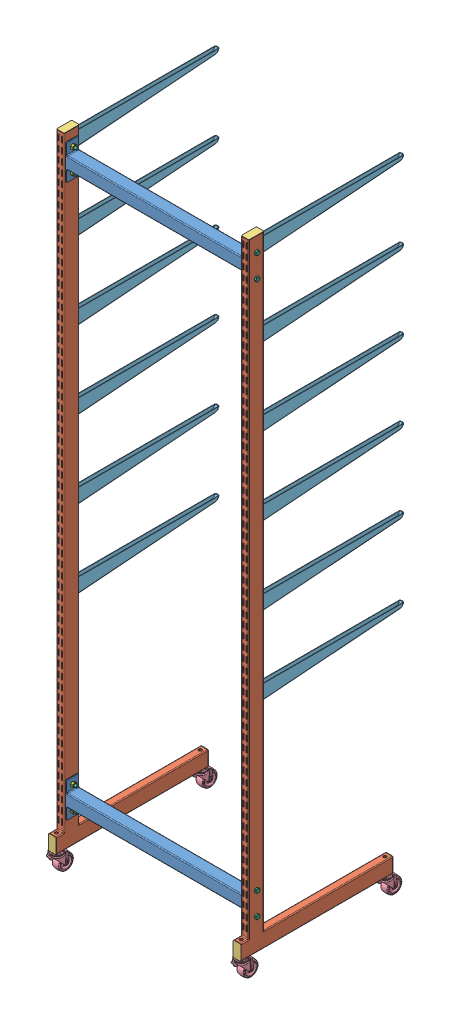
SolidWorks assembly Twin slot shelf, configuration Default. Lengths in mm.
Overall size (666.07 2115 554.23).
43 component instances, 8 part files, 104 mates.
Components (placement in the parent):
- TB-600-1: TB-600 [Default] at (0 2029.5 0) size (585 115 40)
- TB-600-2: TB-600 [Default] at (0 205.5 0) size (585 115 40)
- TSU-F-L-P-1: TSU-F-L-P [Default] at (305 113.5 -25) size (25 2050 500)
- TSU-F-L-P-2: TSU-F-L-P [Default] at (-305 113.5 -25) size (25 2050 500)
- TSU-CAP-1: TSU-CAP [Default] at (-305.1 113.6 -39.9) x (-1 0 0) z (0 0 -1) size (25.2 50.2 6.5)
- TSU-CAP-2: TSU-CAP [Default] at (304.9 113.6 -39.9) x (-1 0 0) z (0 0 -1) size (25.2 50.2 6.5)
- TSU-CAP-3: TSU-CAP [Default] at (305.1 1703.4 -25.1) x (1 0 0) z (0 1 0) size (25.2 50.2 6.5)
- TSU-CAP-4: TSU-CAP [Default] at (304.9 113.6 -360.1) size (25.2 50.2 6.5)
- TSU-CAP-5: TSU-CAP [Default] at (-304.9 1703.4 -25.1) x (1 0 0) z (0 1 0) size (25.2 50.2 6.5)
- TSU-CAP-6: TSU-CAP [Default] at (-304.9 113.6 -360.1) size (25.2 50.2 6.5)
- 2834T320_THREADED-STEM SWIVEL CASTER-1: 2834T320_THREADED-STEM SWIVEL CASTER [2834T32] at (305 82.55 -437.5) x (0 0 -1) z (1 0 0) size (67.73 101.87 56.07)
- 2834T320_THREADED-STEM SWIVEL CASTER-2: 2834T320_THREADED-STEM SWIVEL CASTER [2834T32] at (-305 82.55 37.5) x (0 0 -1) z (1 0 0) size (67.73 101.87 56.07)
- 2834T320_THREADED-STEM SWIVEL CASTER-3: 2834T320_THREADED-STEM SWIVEL CASTER [2834T32] at (305 82.55 37.5) x (0 0 -1) z (1 0 0) size (67.73 101.87 56.07)
- 2834T320_THREADED-STEM SWIVEL CASTER-4: 2834T320_THREADED-STEM SWIVEL CASTER [2834T32] at (-305 82.55 -437.5) x (0 0 -1) z (1 0 0) size (67.73 101.87 56.07)
- TSUB-1: TSUB [Default] at (305 766.5 -25) x (-1 0 0) z (0 0 -1) size (14.07 50.86 484.03)
- TSUB-2: TSUB [Default] at (-305 766.5 -25) x (-1 0 0) z (0 0 -1) size (14.07 50.86 484.03)
- TSUB-3: TSUB [Default] at (-305 1022.5 -25) x (-1 0 0) z (0 0 -1) size (14.07 50.86 484.03)
- TSUB-4: TSUB [Default] at (305 1022.5 -25) x (-1 0 0) z (0 0 -1) size (14.07 50.86 484.03)
- TSUB-5: TSUB [Default] at (-305 1534.5 -25) x (-1 0 0) z (0 0 -1) size (14.07 50.86 484.03)
- TSUB-6: TSUB [Default] at (305 1534.5 -25) x (-1 0 0) z (0 0 -1) size (14.07 50.86 484.03)
- TSUB-7: TSUB [Default] at (-305 2046.5 -25) x (-1 0 0) z (0 0 -1) size (14.07 50.86 484.03)
- TSUB-8: TSUB [Default] at (305 2046.5 -25) x (-1 0 0) z (0 0 -1) size (14.07 50.86 484.03)
- TSUB-9: TSUB [Default] at (-305 1278.5 -25) x (-1 0 0) z (0 0 -1) size (14.07 50.86 484.03)
- TSUB-10: TSUB [Default] at (305 1278.5 -25) x (-1 0 0) z (0 0 -1) size (14.07 50.86 484.03)
- TSUB-11: TSUB [Default] at (-305 1790.5 -25) x (-1 0 0) z (0 0 -1) size (14.07 50.86 484.03)
- TSUB-12: TSUB [Default] at (305 1790.5 -25) x (-1 0 0) z (0 0 -1) size (14.07 50.86 484.03)
- hex bolt gradeab2_bsi-10: hex bolt gradeab2_bsi [BS EN 28765 - M8x1 x 45 x 22-N] at (322.8 2067 0) x (-1 0 0) z (0 -0.924225 -0.381849) size (50.3 15.01 13)
- hex bolt gradeab2_bsi-11: hex bolt gradeab2_bsi [BS EN 28765 - M8x1 x 45 x 22-N] at (322.8 1992 0) x (-1 0 0) z (0 -0.999974 0.007224) size (50.3 15.01 13)
- hex bolt gradeab2_bsi-12: hex bolt gradeab2_bsi [BS EN 28765 - M8x1 x 45 x 22-N] at (-322.8 2067 0) size (50.3 15.01 13)
- hex bolt gradeab2_bsi-13: hex bolt gradeab2_bsi [BS EN 28765 - M8x1 x 45 x 22-N] at (-322.8 1992 0) size (50.3 15.01 13)
- hex bolt gradeab2_bsi-14: hex bolt gradeab2_bsi [BS EN 28765 - M8x1 x 45 x 22-N] at (-322.8 168 0) size (50.3 15.01 13)
- hex bolt gradeab2_bsi-15: hex bolt gradeab2_bsi [BS EN 28765 - M8x1 x 45 x 22-N] at (-322.8 243 0) size (50.3 15.01 13)
- hex bolt gradeab2_bsi-16: hex bolt gradeab2_bsi [BS EN 28765 - M8x1 x 45 x 22-N] at (322.8 168 0) x (-1 0 0) z (0 0.924225 0.381849) size (50.3 15.01 13)
- hex bolt gradeab2_bsi-17: hex bolt gradeab2_bsi [BS EN 28765 - M8x1 x 45 x 22-N] at (322.8 243 0) x (-1 0 0) z (0 -0.924225 -0.381849) size (50.3 15.01 13)
- hex nut gradec_bsi-1: hex nut gradec_bsi [BS EN 24034 - M8 - N] at (281.6 2067 0) x (0 0 1) z (-1 0 0) size (13 15.01 7.9)
- hex nut gradec_bsi-2: hex nut gradec_bsi [BS EN 24034 - M8 - N] at (281.6 1992 0) x (0 0 1) z (-1 0 0) size (13 15.01 7.9)
- hex nut gradec_bsi-3: hex nut gradec_bsi [BS EN 24034 - M8 - N] at (-281.6 2067 0) x (0 0 -1) z (1 0 0) size (13 15.01 7.9)
- hex nut gradec_bsi-4: hex nut gradec_bsi [BS EN 24034 - M8 - N] at (-281.6 1992 0) x (0 0.383049 0.923728) z (1 0 0) size (13 15.01 7.9)
- hex nut gradec_bsi-5: hex nut gradec_bsi [BS EN 24034 - M8 - N] at (-281.6 243 0) x (0 0 -1) z (1 0 0) size (13 15.01 7.9)
- hex nut gradec_bsi-6: hex nut gradec_bsi [BS EN 24034 - M8 - N] at (281.6 243 0) x (0 0 1) z (-1 0 0) size (13 15.01 7.9)
- hex nut gradec_bsi-7: hex nut gradec_bsi [BS EN 24034 - M8 - N] at (281.6 168 0) x (0 0 1) z (-1 0 0) size (13 15.01 7.9)
- hex nut gradec_bsi-8: hex nut gradec_bsi [BS EN 24034 - M8 - N] at (-281.6 168 0) x (0 0 -1) z (1 0 0) size (13 15.01 7.9)
- Part4-1: Part4 [Default] at origin
Mates (geometry in assembly coordinates):
- Coincident5: coincident aligned: plane of TB-600-2 through (0 205.5 0) normal (1 0 0)
- Coincident6: coincident aligned: plane of TB-600-2 through (0 205.5 0) normal (0 0 1)
- Tangent1: tangent anti-aligned: torus of 2834T320_THREADED-STEM SWIVEL CASTER-1
- Concentric5: concentric anti-aligned: cylinder of TSU-F-L-P-1 through (305 113.5 -437.5) axis (0 -1 0) radius 5.1; cylinder of 2834T320_THREADED-STEM SWIVEL CASTER-1 through (305 101.6 -437.5) axis (0 1 0) radius 4.7625
- Coincident7: coincident anti-aligned: plane of TB-600-2 through (292.5 205.5 0) normal (1 0 0); plane of TSU-F-L-P-1 through (292.5 2113.5 -22) normal (-1 0 0)
- Concentric6: concentric anti-aligned: cylinder of TB-600-2 through (292.5 243 0) axis (-1 0 0) radius 4.5; cylinder of TSU-F-L-P-1 through (290.9 243 0) axis (1 0 0) radius 4.5
- Coincident8: coincident anti-aligned: plane of TSU-F-L-P-1 through (305 63.5 -450) normal (0 -1 0); plane of 2834T320_THREADED-STEM SWIVEL CASTER-1 through (305 63.5 -421.3957) normal (0 1 0)
- Concentric7: concentric anti-aligned: cylinder of TB-600-1 through (292.5 2067 0) axis (-1 0 0) radius 4.5; cylinder of TSU-F-L-P-1 through (292.5 2067 0) axis (1 0 0) radius 4.5
- Coincident9: coincident anti-aligned: plane of TB-600-1 through (292.5 2029.5 0) normal (1 0 0); plane of TSU-F-L-P-1 through (292.5 2113.5 -22) normal (-1 0 0)
- Concentric8: concentric aligned: cylinder of TB-600-2 through (-292.5 168 0) axis (1 0 0) radius 4.5; cylinder of TSU-F-L-P-2 through (-319.1 168 0) axis (1 0 0) radius 4.5
- Coincident10: coincident anti-aligned: plane of TB-600-2 through (-292.5 205.5 0) normal (-1 0 0); plane of TSU-F-L-P-2 through (-292.5 2113.5 -22) normal (1 0 0)
- Concentric9: concentric anti-aligned: cylinder of TSU-F-L-P-2 through (-305 113.5 -437.5) axis (0 -1 0) radius 5.1; cylinder of 2834T320_THREADED-STEM SWIVEL CASTER-4 through (-305 101.6 -437.5) axis (0 1 0) radius 4.7625
- Concentric10: concentric aligned: cylinder of TB-600-1 through (-292.5 1992 0) axis (1 0 0) radius 4.5; cylinder of TSU-F-L-P-2 through (-317.5 1992 0) axis (1 0 0) radius 4.5
- Concentric11: concentric aligned: cylinder of TB-600-1 through (-292.5 2067 0) axis (1 0 0) radius 4.5; cylinder of TSU-F-L-P-2 through (-317.5 2067 0) axis (1 0 0) radius 4.5
- Parallel4: parallel aligned: plane of TSU-F-L-P-1 through (317.5 2113.5 -22) normal (1 0 0); plane of 2834T320_THREADED-STEM SWIVEL CASTER-1 through (316.9062 47.2916 -458.1375) normal (1 0 0)
- Coincident16: coincident anti-aligned: plane of TSU-F-L-P-2 through (-305 63.5 -450) normal (0 -1 0); plane of 2834T320_THREADED-STEM SWIVEL CASTER-4 through (-305 63.5 -421.3957) normal (0 1 0)
- Concentric12: concentric anti-aligned: cylinder of TSU-F-L-P-1 through (305 113.5 37.5) axis (0 -1 0) radius 5.1; cylinder of 2834T320_THREADED-STEM SWIVEL CASTER-3 through (305 101.6 37.5) axis (0 1 0) radius 4.7625
- Coincident17: coincident anti-aligned: plane of TSU-F-L-P-1 through (305 63.5 -450) normal (0 -1 0); plane of 2834T320_THREADED-STEM SWIVEL CASTER-3 through (305 63.5 53.6043) normal (0 1 0)
- Coincident18: coincident aligned: plane of 2834T320_THREADED-STEM SWIVEL CASTER-1 through (316.9062 47.2916 -458.1375) normal (1 0 0); plane of 2834T320_THREADED-STEM SWIVEL CASTER-3 through (316.9062 47.2916 16.8625) normal (1 0 0)
- Concentric13: concentric anti-aligned: cylinder of TSU-F-L-P-2 through (-305 113.5 37.5) axis (0 -1 0) radius 5.1; cylinder of 2834T320_THREADED-STEM SWIVEL CASTER-2 through (-305 101.6 37.5) axis (0 1 0) radius 4.7625
- Coincident19: coincident anti-aligned: plane of TSU-F-L-P-2 through (-305 63.5 -450) normal (0 -1 0); plane of 2834T320_THREADED-STEM SWIVEL CASTER-2 through (-305 63.5 53.6043) normal (0 1 0)
- Parallel6: parallel aligned: plane of TSU-F-L-P-2 through (-317.5 2113.5 -22) normal (-1 0 0); plane of 2834T320_THREADED-STEM SWIVEL CASTER-2 through (-316.9062 47.2916 16.8625) normal (-1 0 0)
- Coincident21: coincident anti-aligned: plane of TSU-F-L-P-1 through (294 2113.5 0) normal (1 0 0); plane of TSU-CAP-4 through (294 113.6 45) normal (-1 0 0)
- Coincident22: coincident anti-aligned: plane of TSU-F-L-P-1 through (314.5 112 -450) normal (0 -1 0); plane of TSU-CAP-4 through (304.9 112 45) normal (0 1 0)
- Coincident23: coincident anti-aligned: plane of TSU-F-L-P-1 through (314.5 110.5 50) normal (0 0 1); plane of TSU-CAP-4 through (304.9 113.6 50) normal (0 0 -1)
- Coincident24: coincident anti-aligned: plane of TSU-F-L-P-2 through (-294 2113.5 0) normal (-1 0 0); plane of TSU-CAP-6 through (-294 113.6 45) normal (1 0 0)
- Coincident25: coincident anti-aligned: plane of TSU-F-L-P-2 through (-295.5 112 -450) normal (0 -1 0); plane of TSU-CAP-6 through (-304.9 112 45) normal (0 1 0)
- Coincident26: coincident anti-aligned: plane of TSU-F-L-P-2 through (-295.5 110.5 50) normal (0 0 1); plane of TSU-CAP-6 through (-304.9 113.6 50) normal (0 0 -1)
- Coincident27: coincident anti-aligned: plane of TSU-F-L-P-1 through (294 2113.5 0) normal (1 0 0); plane of TSU-CAP-2 through (294 113.6 -445) normal (-1 0 0)
- Coincident28: coincident anti-aligned: plane of TSU-F-L-P-1 through (314.5 112 -450) normal (0 -1 0); plane of TSU-CAP-2 through (304.9 112 -445) normal (0 1 0)
- Coincident29: coincident anti-aligned: plane of TSU-F-L-P-1 through (314.5 110.5 -450) normal (0 0 -1); plane of TSU-CAP-2 through (304.9 113.6 -450) normal (0 0 1)
- Coincident30: coincident anti-aligned: plane of TSU-F-L-P-2 through (-316 2113.5 0) normal (1 0 0); plane of TSU-CAP-1 through (-316 113.6 -445) normal (-1 0 0)
- Coincident31: coincident anti-aligned: plane of TSU-F-L-P-2 through (-295.5 112 -450) normal (0 -1 0); plane of TSU-CAP-1 through (-305.1 112 -445) normal (0 1 0)
- Coincident32: coincident anti-aligned: plane of TSU-F-L-P-2 through (-295.5 110.5 -450) normal (0 0 -1); plane of TSU-CAP-1 through (-305.1 113.6 -450) normal (0 0 1)
- Coincident33: coincident anti-aligned: plane of TSU-F-L-P-1 through (316 2113.5 0) normal (-1 0 0); plane of TSU-CAP-3 through (316 2108.5 -25.1) normal (1 0 0)
- Coincident34: coincident anti-aligned: plane of TSU-F-L-P-1 through (314.5 2113.5 -23.5) normal (0 0 1); plane of TSU-CAP-3 through (305.1 2108.5 -23.5) normal (0 0 -1)
- Coincident35: coincident anti-aligned: plane of TSU-F-L-P-1 through (314.5 2113.5 -22) normal (0 1 0); plane of TSU-CAP-3 through (305.1 2113.5 -25.1) normal (0 -1 0)
- Coincident36: coincident anti-aligned: plane of TSU-F-L-P-2 through (-294 2113.5 0) normal (-1 0 0); plane of TSU-CAP-5 through (-294 2108.5 -25.1) normal (1 0 0)
- Coincident37: coincident anti-aligned: plane of TSU-F-L-P-2 through (-295.5 2113.5 -23.5) normal (0 0 1); plane of TSU-CAP-5 through (-304.9 2108.5 -23.5) normal (0 0 -1)
- Coincident38: coincident anti-aligned: plane of TSU-F-L-P-2 through (-295.5 2113.5 -22) normal (0 1 0); plane of TSU-CAP-5 through (-304.9 2113.5 -25.1) normal (0 -1 0)
- Parallel7: parallel aligned: plane of TSU-F-L-P-2 through (-292.5 2113.5 -22) normal (1 0 0); plane of 2834T320_THREADED-STEM SWIVEL CASTER-4 through (-293.0938 47.2916 -458.1375) normal (1 0 0)
- Coincident41: coincident anti-aligned: plane of TSU-F-L-P-1 through (298 273.5 0.001) normal (1 0 0); plane of TSUB-1 through (298 766.5 -25) normal (-1 0 0)
- Coincident42: coincident anti-aligned: plane of TSU-F-L-P-1 through (305 2113.5 -25) normal (0 0 -1); plane of TSUB-1 through (312 766.5 -25) normal (0 0 1)
- Parallel8: parallel: line of TSU-F-L-P-1 through (309 342 -23.5) axis (0 0 -1); plane of TSUB-1 through (298 816.5 -25) normal (0 1 0)
- Coincident46: coincident anti-aligned: plane of TSU-F-L-P-2 through (-312 369.5 0.001) normal (1 0 0); plane of TSUB-2 through (-312 766.5 -25) normal (-1 0 0)
- Coincident47: coincident anti-aligned: plane of TSU-F-L-P-2 through (-305 2113.5 -25) normal (0 0 -1); plane of TSUB-2 through (-312 766.5 -25) normal (0 0 1)
- Coincident49: coincident anti-aligned: plane of TSU-F-L-P-1 through (312 1041.5 0.001) normal (-1 0 0); plane of TSUB-4 through (312 1022.5 -25) normal (1 0 0)
- Coincident50: coincident anti-aligned: plane of TSU-F-L-P-1 through (305 2113.5 -25) normal (0 0 -1); plane of TSUB-4 through (312 1022.5 -25) normal (0 0 1)
- Coincident51: coincident anti-aligned: plane of TSU-F-L-P-2 through (-298 1073.5 0.001) normal (-1 0 0); plane of TSUB-3 through (-298 1022.5 -25) normal (1 0 0)
- Coincident52: coincident anti-aligned: plane of TSU-F-L-P-2 through (-305 2113.5 -25) normal (0 0 -1); plane of TSUB-3 through (-312 1022.5 -25) normal (0 0 1)
- Coincident70: coincident anti-aligned: plane of TSU-F-L-P-1 through (305 2113.5 -25) normal (0 0 -1); plane of TSUB-10 through (298 1278.5 -25) normal (0 0 1)
- Coincident71: coincident anti-aligned: plane of TSU-F-L-P-2 through (-305 2113.5 -25) normal (0 0 -1); plane of TSUB-9 through (-312 1278.5 -25) normal (0 0 1)
- Coincident72: coincident aligned: plane of TSUB-3 through (-298 1022.5 -25) normal (1 0 0); plane of TSUB-9 through (-298 1278.5 -25) normal (1 0 0)
- Coincident73: coincident aligned: plane of TSUB-4 through (298 1022.5 -25) normal (-1 0 0); plane of TSUB-10 through (298 1278.5 -25) normal (-1 0 0)
- Coincident74: coincident anti-aligned: plane of TSU-F-L-P-1 through (305 2113.5 -25) normal (0 0 -1); plane of TSUB-6 through (298 1534.5 -25) normal (0 0 1)
- Coincident75: coincident anti-aligned: plane of TSU-F-L-P-2 through (-305 2113.5 -25) normal (0 0 -1); plane of TSUB-5 through (-312 1534.5 -25) normal (0 0 1)
- Coincident76: coincident aligned: plane of TSUB-5 through (-298 1534.5 -25) normal (1 0 0); plane of TSUB-9 through (-298 1278.5 -25) normal (1 0 0)
- Coincident78: coincident aligned: plane of TSUB-6 through (312 1534.5 -25) normal (1 0 0); plane of TSUB-12 through (312 1790.5 -25) normal (1 0 0)
- Coincident79: coincident aligned: plane of TSUB-6 through (298 1534.5 -25) normal (-1 0 0); plane of TSUB-10 through (298 1278.5 -25) normal (-1 0 0)
- Coincident80: coincident anti-aligned: plane of TSU-F-L-P-1 through (305 2113.5 -25) normal (0 0 -1); plane of TSUB-12 through (298 1790.5 -25) normal (0 0 1)
- Coincident81: coincident anti-aligned: plane of TSU-F-L-P-2 through (-312 1873.5 0.001) normal (1 0 0); plane of TSUB-11 through (-312 1790.5 -25) normal (-1 0 0)
- Coincident82: coincident anti-aligned: plane of TSU-F-L-P-2 through (-305 2113.5 -25) normal (0 0 -1); plane of TSUB-11 through (-312 1790.5 -25) normal (0 0 1)
- Coincident83: coincident anti-aligned: plane of TSU-F-L-P-2 through (-312 1969.5 0.001) normal (1 0 0); plane of TSUB-7 through (-312 2046.5 -25) normal (-1 0 0)
- Coincident84: coincident anti-aligned: plane of TSU-F-L-P-2 through (-305 2113.5 -25) normal (0 0 -1); plane of TSUB-7 through (-312 2046.5 -25) normal (0 0 1)
- Coincident85: coincident anti-aligned: plane of TSU-F-L-P-1 through (298 2001.5 0.001) normal (1 0 0); plane of TSUB-8 through (298 2046.5 -25) normal (-1 0 0)
- Coincident86: coincident anti-aligned: plane of TSU-F-L-P-1 through (305 2113.5 -25) normal (0 0 -1); plane of TSUB-8 through (298 2046.5 -25) normal (0 0 1)
- Coincident89: coincident: line of TSU-F-L-P-1 through (309 2070 -23.5) axis (0 0 -1); plane of TSUB-8 through (333.2603 2070 -25) normal (0 1 0)
- Coincident153: coincident: line of TSU-F-L-P-1 through (312 1814 -23.5) axis (0 0 -1); plane of TSUB-12 through (333.2603 1814 -25) normal (0 1 0)
- Coincident155: coincident: line of TSU-F-L-P-1 through (312 1558 -23.5) axis (0 0 -1); plane of TSUB-6 through (333.2603 1558 -25) normal (0 1 0)
- Coincident157: coincident: line of TSU-F-L-P-1 through (312 1302 -23.5) axis (0 0 -1); plane of TSUB-10 through (333.2603 1302 -25) normal (0 1 0)
- Coincident159: coincident: line of TSU-F-L-P-1 through (312 1046 -23.5) axis (0 0 -1); plane of TSUB-4 through (333.2603 1046 -25) normal (0 1 0)
- Coincident167: coincident: line of TSU-F-L-P-1 through (312 790 -23.5) axis (0 0 -1); plane of TSUB-1 through (333.2603 790 -25) normal (0 1 0)
- Concentric15: concentric aligned: cylinder of TSU-F-L-P-1 through (292.5 2067 0) axis (1 0 0) radius 4.5; cylinder of hex bolt gradeab2_bsi-10 through (322.8 2067 0) axis (1 0 0) radius 4
- Coincident181: coincident anti-aligned: plane of TSU-F-L-P-1 through (317.5 2113.5 -22) normal (1 0 0); plane of hex bolt gradeab2_bsi-10 through (317.5 2069.866 -6.9368) normal (-1 0 0)
- Concentric16: concentric aligned: cylinder of TSU-F-L-P-1 through (292.5 1992 0) axis (1 0 0) radius 4.5; cylinder of hex bolt gradeab2_bsi-11 through (322.8 1992 0) axis (1 0 0) radius 4
- Coincident182: coincident anti-aligned: plane of TSU-F-L-P-1 through (317.5 2113.5 -22) normal (1 0 0); plane of hex bolt gradeab2_bsi-11 through (317.5 1991.9458 -7.5054) normal (-1 0 0)
- Concentric17: concentric anti-aligned: cylinder of TB-600-1 through (-292.5 2067 0) axis (1 0 0) radius 4.5; cylinder of hex bolt gradeab2_bsi-12 through (-322.8 2067 0) axis (-1 0 0) radius 4
- Coincident183: coincident anti-aligned: plane of TSU-F-L-P-2 through (-317.5 2113.5 -22) normal (-1 0 0); plane of hex bolt gradeab2_bsi-12 through (-317.5 2074.5056 0) normal (1 0 0)
- Concentric18: concentric anti-aligned: cylinder of TB-600-1 through (-292.5 1992 0) axis (1 0 0) radius 4.5; cylinder of hex bolt gradeab2_bsi-13 through (-322.8 1992 0) axis (-1 0 0) radius 4
- Coincident184: coincident anti-aligned: plane of TSU-F-L-P-2 through (-317.5 2113.5 -22) normal (-1 0 0); plane of hex bolt gradeab2_bsi-13 through (-317.5 1999.5056 0) normal (1 0 0)
- Concentric19: concentric anti-aligned: cylinder of TB-600-2 through (-292.5 243 0) axis (1 0 0) radius 4.5; cylinder of hex bolt gradeab2_bsi-15 through (-322.8 243 0) axis (-1 0 0) radius 4
- Coincident185: coincident anti-aligned: plane of TSU-F-L-P-2 through (-317.5 2113.5 -22) normal (-1 0 0); plane of hex bolt gradeab2_bsi-15 through (-317.5 250.5056 0) normal (1 0 0)
- Concentric20: concentric anti-aligned: cylinder of TB-600-2 through (-292.5 168 0) axis (1 0 0) radius 4.5; cylinder of hex bolt gradeab2_bsi-14 through (-322.8 168 0) axis (-1 0 0) radius 4
- Coincident186: coincident anti-aligned: plane of TSU-F-L-P-2 through (-317.5 2113.5 -22) normal (-1 0 0); plane of hex bolt gradeab2_bsi-14 through (-317.5 175.5056 0) normal (1 0 0)
- Concentric21: concentric anti-aligned: cylinder of TB-600-2 through (292.5 243 0) axis (-1 0 0) radius 4.5; cylinder of hex bolt gradeab2_bsi-17 through (322.8 243 0) axis (1 0 0) radius 4
- Coincident187: coincident anti-aligned: plane of TSU-F-L-P-1 through (317.5 2113.5 -22) normal (1 0 0); plane of hex bolt gradeab2_bsi-17 through (317.5 245.866 -6.9368) normal (-1 0 0)
- Concentric22: concentric aligned: cylinder of TSU-F-L-P-1 through (290.9 168 0) axis (1 0 0) radius 4.5; cylinder of hex bolt gradeab2_bsi-16 through (322.8 168 0) axis (1 0 0) radius 4
- Coincident188: coincident anti-aligned: plane of TSU-F-L-P-1 through (317.5 2113.5 -22) normal (1 0 0); plane of hex bolt gradeab2_bsi-16 through (317.5 165.134 6.9368) normal (-1 0 0)
- Concentric23: concentric anti-aligned: cylinder of hex bolt gradeab2_bsi-10 through (322.8 2067 0) axis (1 0 0) radius 4; cylinder of hex nut gradec_bsi-1 through (289.5 2067 0) axis (-1 0 0) radius 3.4
- Coincident189: coincident anti-aligned: plane of TB-600-1 through (289.5 2029.5 0) normal (-1 0 0); plane of hex nut gradec_bsi-1 through (289.5 2074.5056 0) normal (1 0 0)
- Concentric24: concentric anti-aligned: cylinder of hex bolt gradeab2_bsi-11 through (322.8 1992 0) axis (1 0 0) radius 4; cylinder of hex nut gradec_bsi-2 through (289.5 1992 0) axis (-1 0 0) radius 3.4
- Coincident190: coincident anti-aligned: plane of TB-600-1 through (289.5 2029.5 0) normal (-1 0 0); plane of hex nut gradec_bsi-2 through (289.5 1999.5056 0) normal (1 0 0)
- Concentric25: concentric anti-aligned: cylinder of hex bolt gradeab2_bsi-12 through (-322.8 2067 0) axis (-1 0 0) radius 4; cylinder of hex nut gradec_bsi-3 through (-289.5 2067 0) axis (1 0 0) radius 3.4
- Coincident191: coincident anti-aligned: plane of TB-600-1 through (-289.5 2029.5 0) normal (1 0 0); plane of hex nut gradec_bsi-3 through (-289.5 2074.5056 0) normal (-1 0 0)
- Concentric26: concentric anti-aligned: cylinder of hex bolt gradeab2_bsi-13 through (-322.8 1992 0) axis (-1 0 0) radius 4; cylinder of hex nut gradec_bsi-4 through (-289.5 1992 0) axis (1 0 0) radius 3.4
- Coincident192: coincident anti-aligned: plane of TB-600-1 through (-289.5 2029.5 0) normal (1 0 0); plane of hex nut gradec_bsi-4 through (-289.5 1985.0669 2.875) normal (-1 0 0)
- Concentric27: concentric anti-aligned: cylinder of hex bolt gradeab2_bsi-15 through (-322.8 243 0) axis (-1 0 0) radius 4; cylinder of hex nut gradec_bsi-5 through (-289.5 243 0) axis (1 0 0) radius 3.4
- Coincident193: coincident anti-aligned: plane of TB-600-2 through (-289.5 205.5 0) normal (1 0 0); plane of hex nut gradec_bsi-5 through (-289.5 250.5056 0) normal (-1 0 0)
- Concentric28: concentric anti-aligned: cylinder of hex bolt gradeab2_bsi-14 through (-322.8 168 0) axis (-1 0 0) radius 4; cylinder of hex nut gradec_bsi-8 through (-289.5 168 0) axis (1 0 0) radius 3.4
- Coincident194: coincident anti-aligned: plane of TB-600-2 through (-289.5 205.5 0) normal (1 0 0); plane of hex nut gradec_bsi-8 through (-289.5 175.5056 0) normal (-1 0 0)
- Concentric29: concentric anti-aligned: cylinder of hex bolt gradeab2_bsi-17 through (322.8 243 0) axis (1 0 0) radius 4; cylinder of hex nut gradec_bsi-6 through (289.5 243 0) axis (-1 0 0) radius 3.4
- Concentric30: concentric anti-aligned: cylinder of hex bolt gradeab2_bsi-16 through (322.8 168 0) axis (1 0 0) radius 4; cylinder of hex nut gradec_bsi-7 through (289.5 168 0) axis (-1 0 0) radius 3.4
- Coincident195: coincident anti-aligned: plane of TB-600-2 through (289.5 205.5 0) normal (-1 0 0); plane of hex nut gradec_bsi-6 through (289.5 250.5056 0) normal (1 0 0)
- Coincident196: coincident anti-aligned: plane of TB-600-2 through (289.5 205.5 0) normal (-1 0 0); plane of hex nut gradec_bsi-7 through (289.5 175.5056 0) normal (1 0 0)
